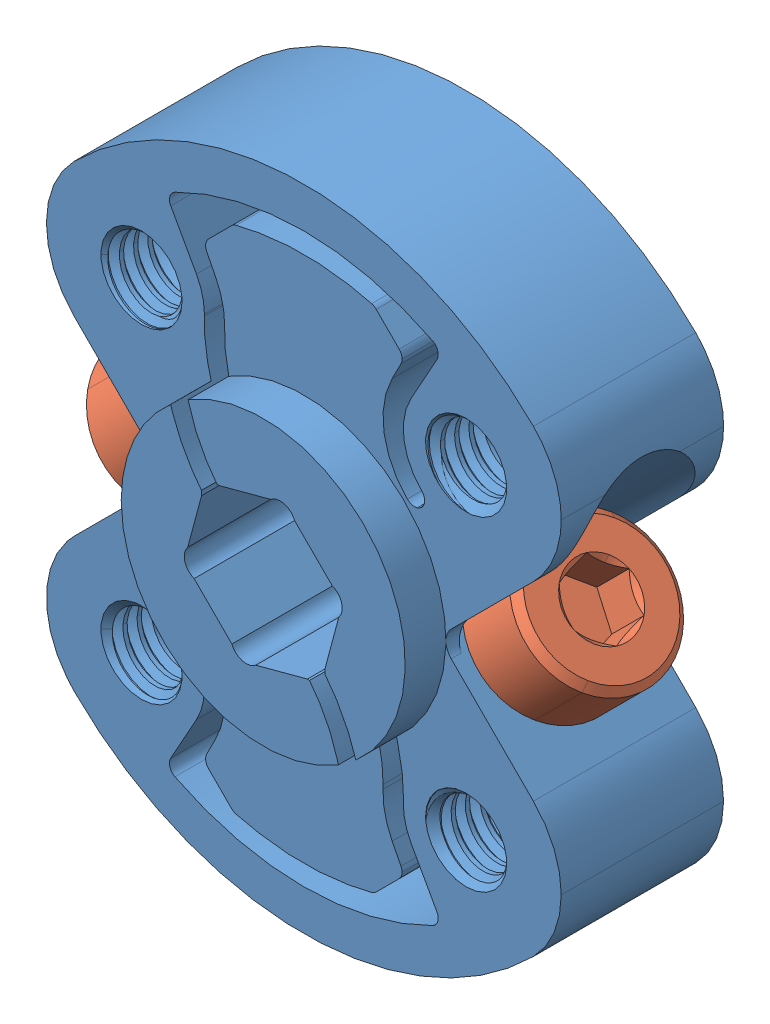
SolidWorks assembly 8mm REX Hub 1309-0016-0008, configuration Default. Lengths in mm.
Overall size (28.36 32 10.95).
3 component instances, 2 part files, 0 mates.
Components (placement in the parent):
- 1309-0016-4008.STEP-1: 1309-0016-4008.STEP [Default] at (-3.9254 17.6745 -10.385) size (25.38 32 10)
- 2800-0004-0014_90128A207.STEP-1: 2800-0004-0014_90128A207.STEP [Default] at (-5.9783 6.5558 -10.385) x (0.5 -0.5 0.707107) z (-0.707107 -0.707107 0) size (7 7 18.01)
- 2800-0004-0014_90128A207.STEP-2: 2800-0004-0014_90128A207.STEP [Default] at (-1.8726 28.7932 -10.385) x (-0.5 0.5 0.707107) z (0.707107 0.707107 0) size (7 7 18.01)
